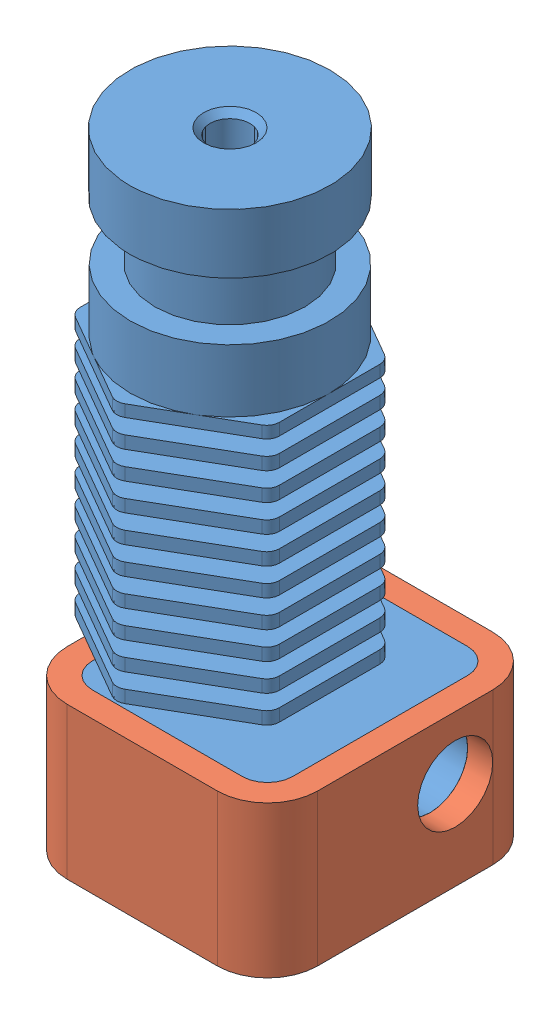
SolidWorks assembly HexagonAssembled, configuration Default. Lengths in mm.
Overall size (20 54.51 24.04).
2 component instances, 2 part files, 0 mates.
Components (placement in the parent):
- HexagonHotEnd-1: HexagonHotEnd [Default] at (-13.8308 34.4544 -1.9967) size (16 54.51 22.04)
- HexagonBlockInsulator-1: HexagonBlockInsulator [Default] at origin size (20 12.11 22)
